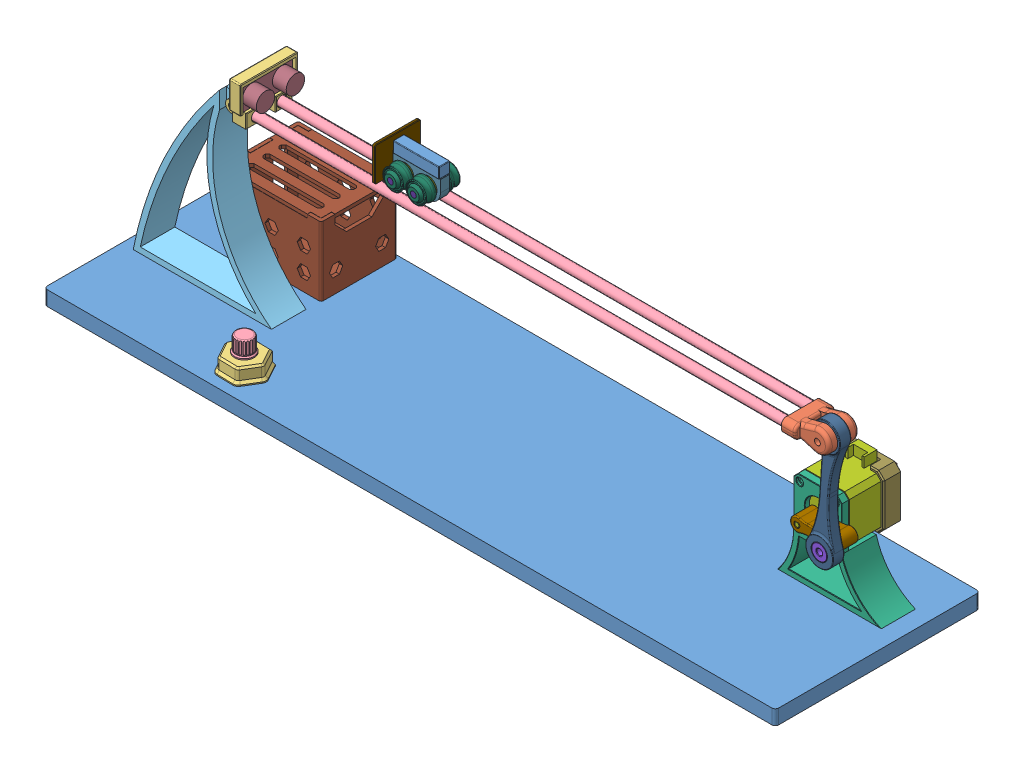
SolidWorks assembly BALL AND BEAM ASSEMBLY, configuration Default. Lengths in mm.
Overall size (635 198.98 177.8).
33 component instances, 23 part files, 49 mates.
Components (placement in the parent):
- Base-1: Base [Default] at origin size (635 12.7 177.8)
- Beam End-1: Beam End [Default] at (263.5 162.9124 6.2) x (0 0 -1) z (1 0.000437 0) size (35 20 37)
- Beam Hinge-1: Beam Hinge [Default] at (-210.5 162.7052 6.2) x (0 0 1) z (-1 -0.000437 0) size (50 36 23.1)
- Dowel-1: Dowel [Default] at (-213.5 162.7039 17.2) x (0.00027 -0.617496 -0.786574) z (1 0.000437 0) size (8.1 8.1 480)
- Dowel-2: Dowel [Default] at (-213.5 162.7039 -4.8) x (-0.000377 0.863431 -0.504466) z (1 0.000437 0) size (8.1 8.1 480)
- Hinge Tower-1: Hinge Tower [Default] at (-247.5 12.7 6.4) size (120 157.5 30)
- Motor Tower-1: Motor Tower [Default] at (247.5 72.7 -17.8) size (90 81 30)
- NEMA-17_38mm-1: NEMA-17_38mm [Default] at (247.5 72.7 -61.8) size (42.3 50.8 62)
- 605ZZ Bearing-1: 605ZZ Bearing [Default] at (278.4971 73.122 6.7) x (0.949664 -0.313269 0) z (0 0 1) size (14 14 5)
- Crank-1: Crank [Default] at (247.5 72.7 -16.3) x (0.999907 0.013613 0) z (0 0 1) size (43 12 18.74)
- Coupler-1: Coupler [Default] at (281.4985 118.0218 6.7) x (-0.066698 -0.997773 0) z (0 0 1) size (114 24 10.57)
- 605ZZ Bearing-2: 605ZZ Bearing [Default] at (284.5 162.9216 1.7) x (0.98331 0.181939 0) z (0 0 1) size (14 14 5)
- 605ZZ Bearing-3: 605ZZ Bearing [Default] at (284.5 162.9216 6.7) x (0.230918 0.972973 0) z (0 0 1) size (14 14 5)
- 605ZZ Bearing-4: 605ZZ Bearing [Default] at (278.4971 73.122 1.7) x (0.998534 0.054119 0) z (0 0 1) size (14 14 5)
- ArduinoBoxTall-1: ArduinoBoxTall [Default] at (-229.4326 12.7 -53.7011) x (1 0 0) z (0 1 0) size (86 66 60)
- AS5600 NEMA-17 Mount-1: AS5600 NEMA-17 Mount [Default] at (247.45 72.65 -61.8) x (1 0 0) z (0 0 -1) size (47.2 47.2 15)
- HC-SR04 Distance Sensor-1: HC-SR04 Distance Sensor [Default] at (-208.5073 179.4561 6.55) x (0 0 -1) z (1 0.000437 0) size (45.3 27.5 18)
- Cart-1: Cart [Default] at (-84.1 175.8024 0.5275) size (46.27 36.44 40)
  - Cart Chassis-1: Cart Chassis [Default] at origin size (42.5 22.5 8)
  - Cart Tire-1: Cart Tire [Default] at (0 0 16) x (0 0 1) z (-0.998863 -0.047663 0) size (11 19.01 19.01)
  - Cart Tire-2: Cart Tire [Default] at (20 0 16) x (0 0 1) z (-0.999998 -0.001816 0) size (11 19.01 19.01)
  - Cart Tire-3: Cart Tire [Default] at (20 0 -8) x (0 0 -1) z (0.583886 0.811836 0) size (11 19.01 19.01)
  - Cart Tire-5: Cart Tire [Default] at (0 0 -8) x (0 0 -1) z (0.957716 -0.287717 0) size (11 19.01 19.01)
  - 5x14x5 Bushing-10: 5x14x5 Bushing [Default] at (0 0 1.5) x (-0.914169 0.405333 0) z (0 0 1) size (13.75 13.75 5)
  - 5x14x5 Bushing-11: 5x14x5 Bushing [Default] at (20 0 1.5) x (-0.914169 0.405333 0) z (0 0 1) size (13.75 13.75 5)
  - Cart Axle-1: Cart Axle [Default] at (0 0 -13) x (0.755413 -0.655249 0) z (0 0 1) size (5 5 34)
  - Cart Axle-2: Cart Axle [Default] at (20 0 -13) x (0.845954 0.533256 0) z (0 0 1) size (5 5 34)
  - Cart Shield-1: Cart Shield [Default] at (-13 8.1762 3.8801) x (0 0 -1) z (1 0 0) size (40 30 2.5)
  - Cart Weight-1: Cart Weight [Default] at (30 14.7625 4) x (0 0 1) z (-1 0 0) size (9.53 9.53 40)
- Drum-1: Drum [Default] at (-172.6868 189.8065 -171.5503) x (0.021153 0.030116 0.999323) z (-0.643527 -0.764545 0.036663) size (50 34 34) (hidden)
- Encoder Cover-1: Encoder Cover [Default] at (247.45 71.65 -78.3) size (21 24.5 11.5)
- Potentiometer Holder-1: Potentiometer Holder [Default] at (-168.976 25.2 62.9872) x (0.999739 0 0.022858) z (0 -1 0) size (37.71 33 12.5)
- Potentiometer Knob-1: Potentiometer Knob [Default] at (-169.0291 39.3428 63.4271) x (0.884857 0 0.465862) z (0 -1 0) size (17 17 13.5)
Mates (geometry in assembly coordinates):
- Coincident1: coincident anti-aligned: plane of Beam Hinge-1 through (-213.5 162.7039 -4.8) normal (1 0.000437 0); plane of Dowel-2 through (-213.5 162.7039 -4.8) normal (-1 -0.000437 0)
- Coincident2: coincident anti-aligned: plane of Beam Hinge-1 through (-213.5 162.7039 17.2) normal (1 0.000437 0); plane of Dowel-1 through (-213.5 162.7039 17.2) normal (-1 -0.000437 0)
- Concentric3: concentric aligned: cylinder of Beam End-1 through (269.5 162.915 17.2) axis (-1 -0.000437 0) radius 4.05; cylinder of Dowel-1 through (266.5 162.9137 17.2) axis (-1 -0.000437 0) radius 4.05
- Concentric4: concentric aligned: cylinder of Beam End-1 through (269.5 162.915 -4.8) axis (-1 -0.000437 0) radius 4.05; cylinder of Dowel-2 through (266.5 162.9137 -4.8) axis (-1 -0.000437 0) radius 4.05
- Coincident3: coincident anti-aligned: plane of Beam End-1 through (266.5 162.9137 17.2) normal (-1 -0.000437 0); plane of Dowel-1 through (266.5 162.9137 17.2) normal (1 0.000437 0)
- Coincident4: coincident anti-aligned: plane of Base-1 through (0 12.7 0) normal (0 1 0); plane of Hinge Tower-1 through (-247.5 12.7 21.4) normal (0 -1 0)
- Concentric5: concentric aligned: cylinder of Beam Hinge-1 through (-222.5 162.7 21.2) axis (0 0 -1) radius 2.55; cylinder of Hinge Tower-1 through (-222.5 162.7 15.3) axis (0 0 -1) radius 2.55
- Coincident6: coincident anti-aligned: plane of Base-1 through (0 12.7 0) normal (0 1 0); plane of Motor Tower-1 through (212.5 12.7 -47.8) normal (0 -1 0)
- Concentric6: concentric anti-aligned: cylinder of Motor Tower-1 through (247.5 72.7 -23.8) axis (0 0 1) radius 11.15; cylinder of NEMA-17_38mm-1 through (247.5 72.7 -21.8) axis (0 0 -1) radius 11
- Coincident7: coincident anti-aligned: plane of Motor Tower-1 through (247.5 72.7 -23.8) normal (0 0 -1); plane of NEMA-17_38mm-1 through (247.5 72.7 -23.8) normal (0 0 1)
- Parallel2: parallel aligned: plane of Motor Tower-1 through (268.5 51.7 -23.8) normal (1 0 0); plane of NEMA-17_38mm-1 through (268.65 72.7 -23.8) normal (1 0 0)
- Concentric9: concentric aligned: cylinder of Beam End-1 through (284.5 162.9216 19.35) axis (0 0 -1) radius 2.6; cylinder of Coupler-1 through (284.5 162.9216 11.7) axis (0 0 -1) radius 7.1
- Width3: width anti-aligned: plane of Beam End-1 through (263.5 162.9124 11.35) normal (0 0 -1); plane of Coupler-1 through (263.5 162.9124 1.05) normal (0 0 1); plane of Beam End-1 through (281.4985 118.0218 10.7) normal (0 0 1); plane of Coupler-1 through (281.4985 118.0218 1.7) normal (0 0 -1)
- Parallel3: parallel aligned: plane of Base-1 through (0 12.7 0) normal (0 1 0); plane of Beam End-1
- Parallel4: parallel aligned: plane of Beam End-1 through (269.4973 168.915 23.7) normal (-0.000437 1 0); plane of Crank-1 through (250.561 68.2413 0.2) normal (0.013613 -0.999907 0)
- Concentric10: concentric aligned: cylinder of 605ZZ Bearing-1 through (278.4971 73.122 11.7) axis (0 0 -1) radius 7; cylinder of Coupler-1 through (278.4971 73.122 11.7) axis (0 0 -1) radius 7.1
- Concentric12: concentric anti-aligned: cylinder of Beam End-1 through (284.5 162.9216 -6.95) axis (0 0 1) radius 2.6; cylinder of 605ZZ Bearing-2 through (284.5 162.9216 6.7) axis (0 0 -1) radius 2.5
- Coincident13: coincident anti-aligned: plane of 605ZZ Bearing-2 through (284.5 162.9216 6.7) normal (0 0 1); plane of 605ZZ Bearing-3 through (284.5 162.9216 6.7) normal (0 0 -1)
- Concentric13: concentric aligned: cylinder of 605ZZ Bearing-2 through (284.5 162.9216 6.7) axis (0 0 -1) radius 7; cylinder of 605ZZ Bearing-3 through (284.5 162.9216 11.7) axis (0 0 -1) radius 7
- Coincident14: coincident aligned: plane of Coupler-1 through (284.5 162.9216 11.7) normal (0 0 1); plane of 605ZZ Bearing-3 through (284.5 162.9216 11.7) normal (0 0 1)
- Concentric14: concentric aligned: cylinder of 605ZZ Bearing-1 through (278.4971 73.122 11.7) axis (0 0 -1) radius 7; cylinder of 605ZZ Bearing-4 through (278.4971 73.122 6.7) axis (0 0 -1) radius 7
- Coincident15: coincident anti-aligned: plane of 605ZZ Bearing-1 through (278.4971 73.122 6.7) normal (0 0 -1); plane of 605ZZ Bearing-4 through (278.4971 73.122 6.7) normal (0 0 1)
- Coincident16: coincident aligned: plane of Coupler-1 through (281.4985 118.0218 1.7) normal (0 0 -1); plane of 605ZZ Bearing-4 through (278.4971 73.122 1.7) normal (0 0 -1)
- Distance4: distance = 67.5 mm aligned: plane of Hinge Tower-1 through (-247.5 12.7 21.4) normal (0 0 1); plane of Base-1 through (-317.5 12.7 88.9) normal (0 0 1)
- Coincident18: coincident anti-aligned: plane of Base-1 through (0 12.7 0) normal (0 1 0); plane of ArduinoBoxLongTall-1 through (-256.3464 12.7 -28.3106) normal (0 -1 0)
- Coincident19: coincident anti-aligned: plane of Base-1 through (0 12.7 0) normal (0 1 0); plane of ArduinoBoxTall-1 through (-229.4326 12.7 -53.7011) normal (0 -1 0)
- Parallel5: parallel aligned: plane of Base-1 through (-317.5 12.7 88.9) normal (0 0 1); plane of ArduinoBoxTall-1 through (-272.4326 72.7 -20.7011) normal (0 0 1)
- Concentric15: concentric anti-aligned: cylinder of Beam Hinge-1 through (-229.4189 182.2507 20.8) axis (0.999568 -0.029377 0) radius 1.85; cylinder of SHARP GPD120 Distance Sensor-1 through (-225.5033 183.3373 21) axis (-0.999483 -0.032143 0) radius 1.6
- Concentric16: concentric anti-aligned: cylinder of Beam Hinge-1 through (-229.4189 182.2507 -16.2) axis (0.999568 -0.029377 0) radius 1.85; cylinder of SHARP GPD120 Distance Sensor-1 through (-225.5033 183.3373 -16) axis (-0.999483 -0.032143 0) radius 1.6
- Coincident20: coincident anti-aligned: plane of Beam Hinge-1 through (-204.5 162.7079 6.2) normal (1 0.000437 0); plane of SHARP GPD120 Distance Sensor-1 through (-227.6522 183.2682 -16) normal (-0.999483 -0.032143 0)
- Distance6: distance = 400 mm: line of Motor Tower-1 through (212.5 12.7 -47.8) axis (0 0 1); line of Hinge Tower-1 through (-187.5 12.7 21.4) axis (0 0 -1)
- Coincident21: coincident anti-aligned: plane of NEMA-17_38mm-1 through (247.5 72.7 -61.8) normal (0 0 -1); plane of AS5600 NEMA-17 Mount-1 through (247.45 72.65 -61.8) normal (0 0 1)
- Coincident24: coincident anti-aligned: plane of NEMA-17_38mm-1 through (247.5 72.7 -61.8) normal (0 0 -1); plane of AS5600 NEMA-17 Mount-1 through (247.45 72.65 -61.8) normal (0 0 1)
- Coincident25: coincident anti-aligned: plane of NEMA-17_38mm-1 through (226.35 72.7 -23.8) normal (-1 0 0); plane of AS5600 NEMA-17 Mount-1 through (226.35 55.35 -66.8) normal (1 0 0)
- Coincident26: coincident anti-aligned: plane of NEMA-17_38mm-1 through (247.5 51.55 -23.8) normal (0 -1 0); plane of AS5600 NEMA-17 Mount-1 through (264.75 51.55 -66.8) normal (0 1 0)
- Coincident28: coincident anti-aligned: plane of Beam Hinge-1 through (-222.5 162.7 15.3) normal (0 0 -1); plane of Hinge Tower-1 through (-222.5 162.7 15.3) normal (0 0 1)
- Concentric17: concentric anti-aligned: cylinder of Beam Hinge-1 through (-216.5 162.7026 17.2) axis (1 0.000437 0) radius 4.05; cylinder of Dowel-1 through (266.5 162.9137 17.2) axis (-1 -0.000437 0) radius 4.05
- Coincident29: coincident anti-aligned: plane of Beam Hinge-1 through (-212.5 162.7044 6.2) normal (1 0.000437 0); plane of HC-SR04 Distance Sensor-1 through (-212.5073 179.4544 6.55) normal (-1 -0.000437 0)
- Coincident30: coincident anti-aligned: plane of Beam Hinge-1 through (-212.5118 189.7044 6.2) normal (0.000437 -1 0); plane of HC-SR04 Distance Sensor-1 through (-206.5118 189.707 29.2) normal (-0.000437 1 0)
- Coincident31: coincident anti-aligned: plane of Beam Hinge-1 through (-212.5 162.7044 29.2) normal (0 0 -1); plane of HC-SR04 Distance Sensor-1 through (-206.5028 169.207 29.2) normal (0 0 1)
- Concentric18: concentric aligned: cylinder of NEMA-17_38mm-1 through (247.5 72.7 0.2) axis (0 0 -1) radius 2.5; cylinder of Crank-1 through (247.5 72.7 0.2) axis (0 0 -1) radius 2.65
- Concentric19: concentric aligned: cylinder of 605ZZ Bearing-1 through (278.4971 73.122 11.7) axis (0 0 -1) radius 2.5; cylinder of Crank-1 through (278.4971 73.122 17.1706) axis (0 0 -1) radius 2.55
- Coincident32: coincident anti-aligned: plane of Crank-1 through (278.4971 73.122 1.7) normal (0 0 1); plane of 605ZZ Bearing-4 through (278.4971 73.122 1.7) normal (0 0 -1)
- Coincident33: coincident anti-aligned: plane of AS5600 NEMA-17 Mount-1 through (247.45 72.65 -66.8) normal (0 0 -1); plane of Encoder Cover-1 through (247.45 71.65 -66.8) normal (0 0 1)
- Width4: width aligned: plane of AS5600 NEMA-17 Mount-1 through (271.05 90.9855 -66.8) normal (1 0 0); plane of Encoder Cover-1 through (223.85 54.3145 -66.8) normal (-1 0 0); plane of AS5600 NEMA-17 Mount-1 through (256.45 71.65 -66.8) normal (1 0 0); plane of Encoder Cover-1 through (238.45 71.65 -66.8) normal (-1 0 0)
- Coincident34: coincident aligned: plane of NEMA-17_38mm-1 through (247.5 72.7 0.2) normal (0 0 1); plane of Crank-1 through (247.5 72.7 0.2) normal (0 0 1)
- Distance7: distance = 10 mm: line of Hinge Tower-1 through (-307.5 12.7 21.4) axis (0 0 -1); line of Base-1 through (-317.5 12.7 -85.9) axis (0 0 1)
- Width5: width aligned: plane of AS5600 NEMA-17 Mount-1 through (265.7855 49.05 -66.8) normal (0 -1 0); plane of Encoder Cover-1 through (229.1145 96.25 -66.8) normal (0 1 0); plane of AS5600 NEMA-17 Mount-1 through (247.45 61.15 -76.8) normal (0 -1 0); plane of Encoder Cover-1 through (247.45 84.15 -66.8) normal (0 1 0)
- Coincident37: coincident anti-aligned: plane of Base-1 through (0 12.7 0) normal (0 1 0); plane of Potentiometer Holder-1 through (-168.976 12.7 62.9872) normal (0 -1 0)
